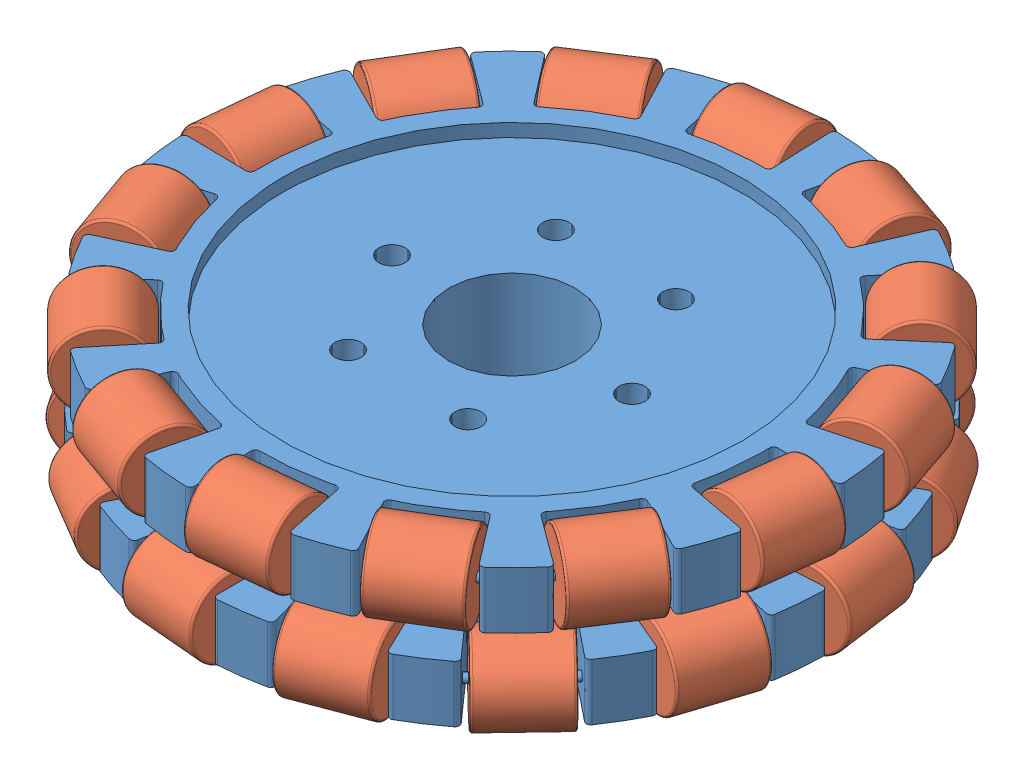
SolidWorks assembly Omni Wheel 152mm, configuration Default. Lengths in mm.
Overall size (157.73 42.93 157.76).
30 component instances, 2 part files, 0 mates.
Components (placement in the parent):
- Omni Wheel 152mm.iam-1: Omni Wheel 152mm.iam [Default] at origin size (157.73 42.93 157.76)
  - Part4.ipt-1: Part4.ipt [Default] at origin size (144.98 32 144.93)
  - WHEEL.ipt-1: WHEEL.ipt [Default] at (54.1393 -10 39.349) x (0.648891 -0.44482 0.617313) z (-0.322279 -0.89562 -0.306596) size (18 17.5 18)
  - WHEEL.ipt-2: WHEEL.ipt [Default] at (65.8507 -10 11.9624) x (0.852471 -0.44482 0.274641) z (-0.42339 -0.89562 -0.136404) size (18 17.5 18)
  - WHEEL.ipt-3: WHEEL.ipt [Default] at (64.5198 -10 -17.7935) x (0.887213 -0.44482 -0.122426) z (-0.440645 -0.89562 0.060804) size (18 17.5 18)
  - WHEEL.ipt-4: WHEEL.ipt [Default] at (50.4103 -10 -44.0252) x (0.746235 -0.44482 -0.495245) z (-0.370627 -0.89562 0.245969) size (18 17.5 18)
  - WHEEL.ipt-5: WHEEL.ipt [Default] at (26.3166 -10 -61.5374) x (0.45746 -0.44482 -0.769978) z (-0.227203 -0.89562 0.382419) size (18 17.5 18)
  - WHEEL.ipt-6: WHEEL.ipt [Default] at (-2.9893 -10 -66.8616) x (0.078081 -0.44482 -0.89221) z (-0.03878 -0.89562 0.443127) size (18 17.5 18)
  - WHEEL.ipt-7: WHEEL.ipt [Default] at (-31.7032 -10 -58.9434) x (-0.316763 -0.44482 -0.837733) z (0.157324 -0.89562 0.41607) size (18 17.5 18)
  - WHEEL.ipt-8: WHEEL.ipt [Default] at (-54.138 -10 -39.3509) x (-0.648869 -0.44482 -0.617336) z (0.322269 -0.89562 0.306607) size (18 17.5 18)
  - WHEEL.ipt-9: WHEEL.ipt [Default] at (-65.8503 -10 -11.9647) x (-0.852462 -0.44482 -0.274671) z (0.423385 -0.89562 0.136419) size (18 17.5 18)
  - WHEEL.ipt-10: WHEEL.ipt [Default] at (-64.5204 -10 17.7912) x (-0.887217 -0.44482 0.122395) z (0.440647 -0.89562 -0.060789) size (18 17.5 18)
  - WHEEL.ipt-11: WHEEL.ipt [Default] at (-50.4118 -10 44.0235) x (-0.746253 -0.44482 0.495219) z (0.370635 -0.89562 -0.245957) size (18 17.5 18)
  - WHEEL.ipt-12: WHEEL.ipt [Default] at (-26.3187 -10 61.5365) x (-0.457487 -0.44482 0.769962) z (0.227216 -0.89562 -0.382411) size (18 17.5 18)
  - WHEEL.ipt-13: WHEEL.ipt [Default] at (2.987 -10 66.8618) x (-0.078112 -0.44482 0.892207) z (0.038795 -0.89562 -0.443125) size (18 17.5 18)
  - WHEEL.ipt-14: WHEEL.ipt [Default] at (31.7011 -10 58.9445) x (0.316734 -0.44482 0.837744) z (-0.15731 -0.89562 -0.416075) size (18 17.5 18)
  - WHEEL.ipt-15: WHEEL.ipt [Default] at (13.0319 10.0739 -65.6262) x (0.07524 -0.980119 -0.183592) z (-0.321212 -0.198123 0.926051) size (18 17.5 18)
  - WHEEL.ipt-16: WHEEL.ipt [Default] at (-16.7325 10.0739 -64.7816) x (-0.011867 -0.980119 -0.198057) z (0.112391 -0.198123 0.973712) size (18 17.5 18)
  - WHEEL.ipt-17: WHEEL.ipt [Default] at (-43.1829 10.0739 -51.1064) x (-0.096625 -0.980119 -0.173294) z (0.523735 -0.198123 0.828522) size (18 17.5 18)
  - WHEEL.ipt-18: WHEEL.ipt [Default] at (-61.0806 10.0739 -27.3092) x (-0.162245 -0.980119 -0.11421) z (0.831348 -0.198123 0.519237) size (18 17.5 18)
  - WHEEL.ipt-19: WHEEL.ipt [Default] at (-66.8807 10.0739 1.8967) x (-0.195731 -0.980119 -0.032505) z (0.974307 -0.198123 0.107113) size (18 17.5 18)
  - WHEEL.ipt-20: WHEEL.ipt [Default] at (-59.4346 10.0739 30.7271) x (-0.190451 -0.980119 0.055638) z (0.924296 -0.198123 -0.326226) size (18 17.5 18)
  - WHEEL.ipt-21: WHEEL.ipt [Default] at (-40.2171 10.0739 53.4717) x (-0.147451 -0.980119 0.132761) z (0.691221 -0.198123 -0.694953) size (18 17.5 18)
  - WHEEL.ipt-22: WHEEL.ipt [Default] at (-13.0342 10.0739 65.6258) x (-0.075247 -0.980119 0.18359) z (0.321245 -0.198123 -0.92604) size (18 17.5 18)
  - WHEEL.ipt-23: WHEEL.ipt [Default] at (16.7303 10.0739 64.7822) x (0.011861 -0.980119 0.198057) z (-0.112357 -0.198123 -0.973716) size (18 17.5 18)
  - WHEEL.ipt-24: WHEEL.ipt [Default] at (43.1811 10.0739 51.1079) x (0.096619 -0.980119 0.173298) z (-0.523706 -0.198123 -0.828541) size (18 17.5 18)
  - WHEEL.ipt-25: WHEEL.ipt [Default] at (61.0796 10.0739 27.3114) x (0.162241 -0.980119 0.114215) z (-0.83133 -0.198123 -0.519266) size (18 17.5 18)
  - WHEEL.ipt-26: WHEEL.ipt [Default] at (66.8808 10.0739 -1.8944) x (0.19573 -0.980119 0.032512) z (-0.974303 -0.198123 -0.107147) size (18 17.5 18)
  - WHEEL.ipt-27: WHEEL.ipt [Default] at (59.4357 10.0739 -30.725) x (0.190453 -0.980119 -0.055631) z (-0.924308 -0.198123 0.326194) size (18 17.5 18)
  - WHEEL.ipt-28: WHEEL.ipt [Default] at (40.2189 10.0739 -53.4703) x (0.147456 -0.980119 -0.132756) z (-0.691246 -0.198123 0.694929) size (18 17.5 18)
